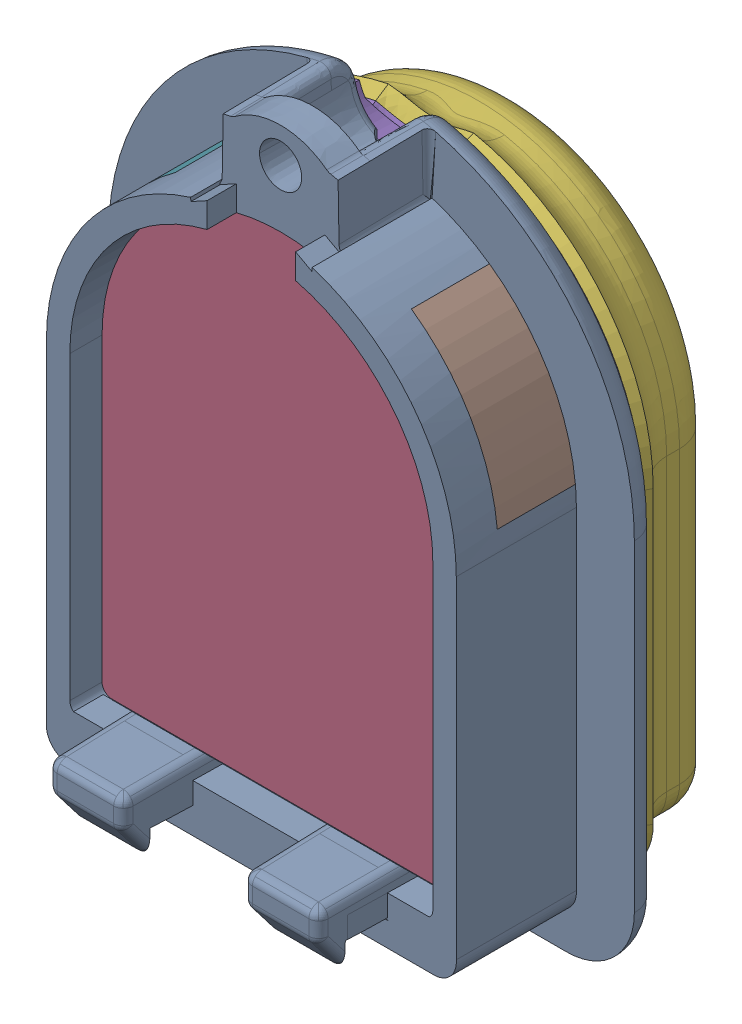
SolidWorks assembly ChessBoardDesign, configuration 默认. Lengths in mm.
Overall size (26.95 34.26 17.16).
8 component instances, 7 part files, 21 mates.
Components (placement in the parent):
- Tip1-1: Tip1 [默认] at (-1.9035 7.7463 -5.5591) size (26.95 34.26 11.2)
- lensnew-1: lensnew [默认] at (-1.9035 7.7463 -5.5591) size (18.6 25.2 6)
- Skin0.2-1: Skin0.2 [默认] at (-1.9035 7.4963 -5.5591) x (-1 0 0) z (0 0 -1) size (23.9 30.06 5.2)
- Skin1-1: Skin1 [默认] at (-1.9035 7.4963 -5.5591) x (-1 0 0) z (0 0 -1) size (22.77 29.32 5.25)
- sidelens1-1: sidelens1 [默认] at (-1.9035 7.7463 -6.2091) size (6.4 7.71 4)
- sidelens1-2: sidelens1 [默认] at (-1.9035 7.7463 2.0909) x (-1 0 0) z (0 0 -1) size (6.4 7.71 4)
- bottomlens-1: bottomlens [默认] at (-5.9035 -10.5037 0.4409) x (1 0 0) z (0 1 0) size (8 4.5 2.35)
- ChessboardDigit-1: ChessboardDigit [默认] at (-15.1693 -0.6894 -10.3591) x (0 1 0) z (0 0 -1) size (22.5 14.3 0.4)
Mates (geometry in assembly coordinates):
- 同心1: concentric aligned: cylinder of Tip1-1 through (-1.9035 7.7463 51.2878) axis (0 0 -1) radius 9.3; cylinder of lensnew-1 through (-1.9035 7.7463 0.4409) axis (0 0 -1) radius 9.3
- 重合1: coincident anti-aligned: plane of Tip1-1 through (-1.9035 -8.1537 51.2878) normal (0 1 0); plane of lensnew-1 through (-11.2035 -8.1537 0.4409) normal (0 -1 0)
- 重合2: coincident aligned: plane of Tip1-1 through (-1.964 4.3089 -5.5591) normal (0 0 -1); plane of lensnew-1 through (-1.9035 7.7463 -5.5591) normal (0 0 -1)
- 重合3: coincident anti-aligned: plane of lensnew-1 through (-1.9035 7.7463 -5.5591) normal (0 0 -1); plane of Skin0.2-1 through (-1.9035 7.4963 -5.5591) normal (0 0 1)
- 同心2: concentric aligned: cone of Tip1-1 through (-1.9035 19.9963 -1.0591) axis (0 0 1); cylinder of Skin0.2-1 through (-1.9035 19.9963 -6.3091) axis (0 0 1) radius 2.75
- 宽度1: width aligned: plane of Skin0.2-1 through (-13.8535 7.4963 -5.5591) normal (-1 0 0); plane of Skin0.2-1 through (10.0465 7.4963 -5.5591) normal (1 0 0); plane of Tip1-1 through (-12.4035 7.7463 2.0909) normal (-1 0 0); plane of Tip1-1 through (8.5965 7.7463 2.0909) normal (1 0 0)
- 重合4: coincident anti-aligned: plane of Skin0.2-1 through (-1.9035 7.4963 -10.7591) normal (0 0 -1); plane of Skin1-1 through (-1.9035 7.4963 -10.7591) normal (0 0 1)
- 宽度2: width anti-aligned: plane of Skin0.2-1 through (-13.8535 7.4963 -5.5591) normal (-1 0 0); plane of Skin0.2-1 through (10.0465 7.4963 -5.5591) normal (1 0 0); plane of Skin1-1 through (-12.8325 0.0508 -6.2245) normal (-0.891007 0 0.45399); plane of Skin1-1 through (9.0255 0.0508 -6.2245) normal (0.891007 0 0.45399)
- 重合5: coincident aligned: cone of Skin0.2-1 through (-1.9035 7.4963 -6.2245) axis (0 0 1); cone of Skin1-1 through (-1.9035 7.4963 -6.2245) axis (0 0 1)
- 重合6: coincident anti-aligned: plane of Tip1-1 through (-16.7251 9.2061 -4.0591) normal (0.104528 0.994522 0); plane of sidelens1-1 through (8.4147 6.5638 -0.0591) normal (-0.104528 -0.994522 0)
- 重合7: coincident anti-aligned: plane of Tip1-1 through (-1.9035 7.7463 -4.0591) normal (0 0 1); plane of sidelens1-1 through (8.4147 6.5638 -4.0591) normal (0 0 -1)
- 同心3: concentric aligned: cylinder of Tip1-1 through (-1.9035 7.7463 2.0909) axis (0 0 -1) radius 10.5; cylinder of sidelens1-1 through (-1.9035 7.7463 -0.0591) axis (0 0 -1) radius 10.5
- 同心4: concentric anti-aligned: cylinder of Tip1-1 through (-1.9035 7.7463 2.0909) axis (0 0 -1) radius 10.5; cylinder of sidelens1-2 through (-1.9035 7.7463 -4.0591) axis (0 0 1) radius 10.5
- 重合8: coincident anti-aligned: plane of Tip1-1 through (12.0819 17.1622 -0.0591) normal (0.104528 -0.994522 0); plane of sidelens1-2 through (-13.0579 14.5199 -4.0591) normal (-0.104528 0.994522 0)
- 重合9: coincident anti-aligned: plane of Tip1-1 through (-1.9035 7.7463 -4.0591) normal (0 0 1); plane of sidelens1-2 through (-1.9035 7.7463 -4.0591) normal (0 0 -1)
- 重合10: coincident anti-aligned: plane of lensnew-1 through (-11.2035 -8.1537 0.4409) normal (0 -1 0); plane of bottomlens-1 through (-5.9035 -8.1537 0.4409) normal (0 1 0)
- 重合11: coincident anti-aligned: plane of Tip1-1 through (-5.9035 -18.1537 0.4409) normal (0 0 -1); plane of bottomlens-1 through (-5.9035 -8.1537 0.4409) normal (0 0 1)
- 重合12: coincident anti-aligned: plane of Tip1-1 through (2.0965 -18.1537 0.4409) normal (-1 0 0); plane of bottomlens-1 through (2.0965 -8.1537 0.4409) normal (1 0 0)
- 宽度4: width aligned: plane of Tip1-1 through (8.5965 7.7463 2.0909) normal (1 0 0); plane of ChessboardDigit-1 through (-12.4035 7.7463 2.0909) normal (-1 0 0); plane of Tip1-1 through (5.2465 4.9053 -10.7591) normal (1 0 0); plane of ChessboardDigit-1 through (-9.0535 9.0053 -10.7591) normal (-1 0 0)
- 距离2: distance = 2 mm aligned: plane of Skin1-1 through (7.3875 -9.3947 -5.5591) normal (0 -1 0); plane of ChessboardDigit-1 through (-2.9535 -7.3947 -10.7591) normal (0 -1 0)
- 重合14: coincident aligned: plane of Skin0.2-1 through (-1.9035 7.4963 -10.7591) normal (0 0 -1); plane of ChessboardDigit-1 through (-11.0693 7.5106 -10.7591) normal (0 0 -1)
